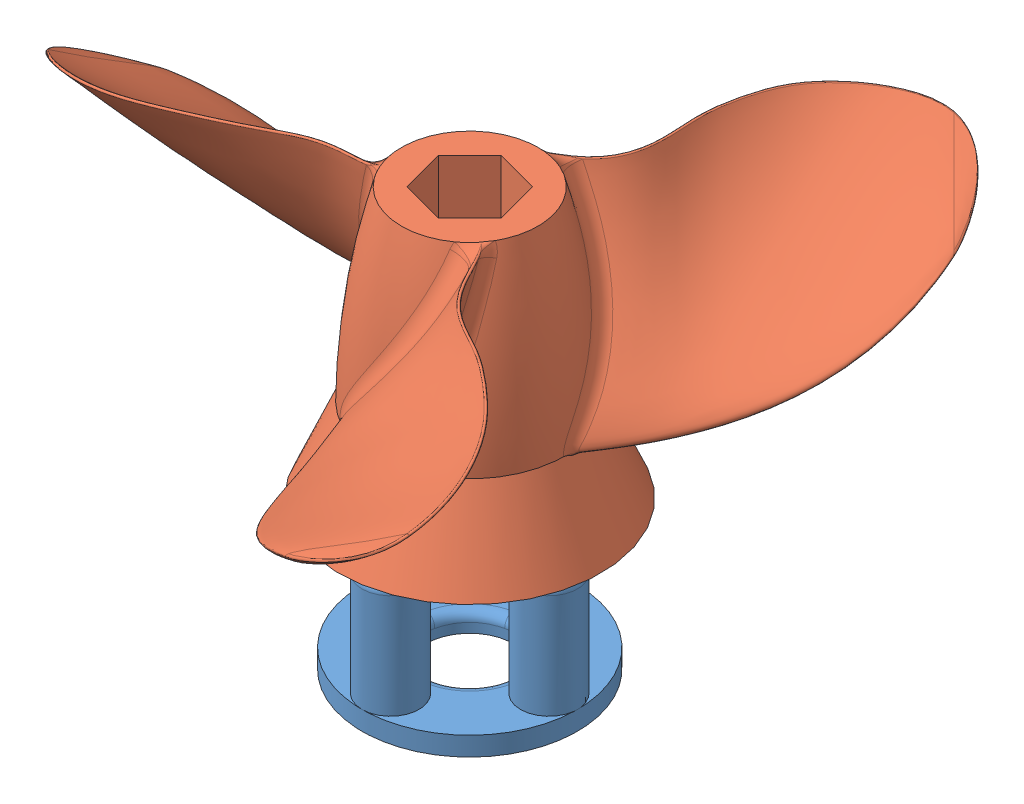
SolidWorks assembly Ensamblaje2, configuration Predeterminado. Lengths in mm.
Overall size (97.89 44.16 97.89).
2 component instances, 2 part files, 1 mates.
Components (placement in the parent):
- SoporteHelice-1: SoporteHelice [Predeterminado] at (-4.2496 -5.8693 22.8253) size (22.83 14.01 22.83)
- turbina-1: turbina [Predeterminado] at (-4.2496 18.1845 22.8253) x (0 1 0) z (-0.708046 0 0.706166) size (28.51 68.31 70.13)
Mates (geometry in assembly coordinates):
- Concéntrica1: concentric aligned: cylinder of SoporteHelice-1 through (-4.2496 -8.6693 22.8253) axis (0 1 0) radius 4.65; cylinder of turbina-1 through (-4.2496 -71.8155 22.8253) axis (0 1 0) radius 2.5
